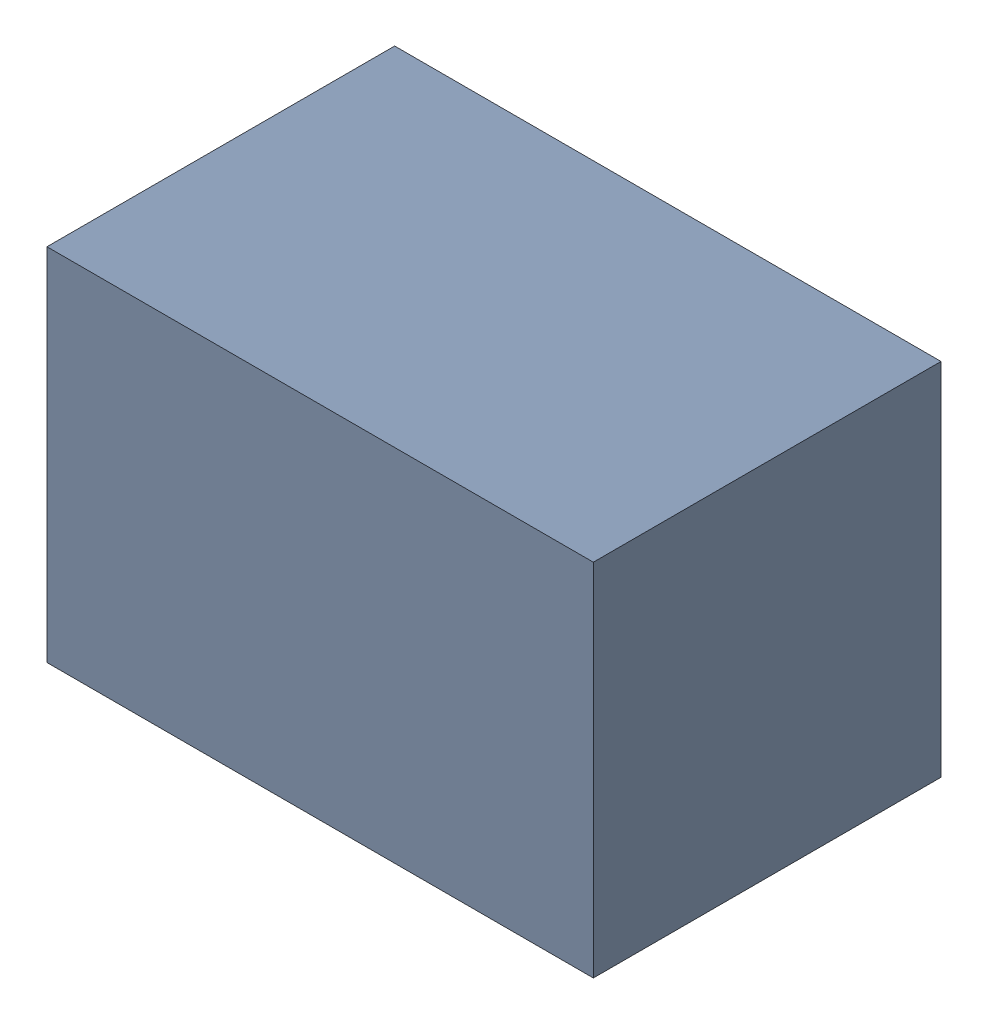
SolidWorks assembly D2-1, configuration Default. Lengths in mm.
Overall size (2.2 1.45 1.4).
2 component instances, 1 part files, 0 mates.
Components (placement in the parent):
- 959210024-1-1: 959210024-1 [Default] at (155.107 90.769 0) size (2.2 1.45 1.4)
  - Extruded-61-1: Extruded-61 [Default] at origin size (2.2 1.45 1.4)
